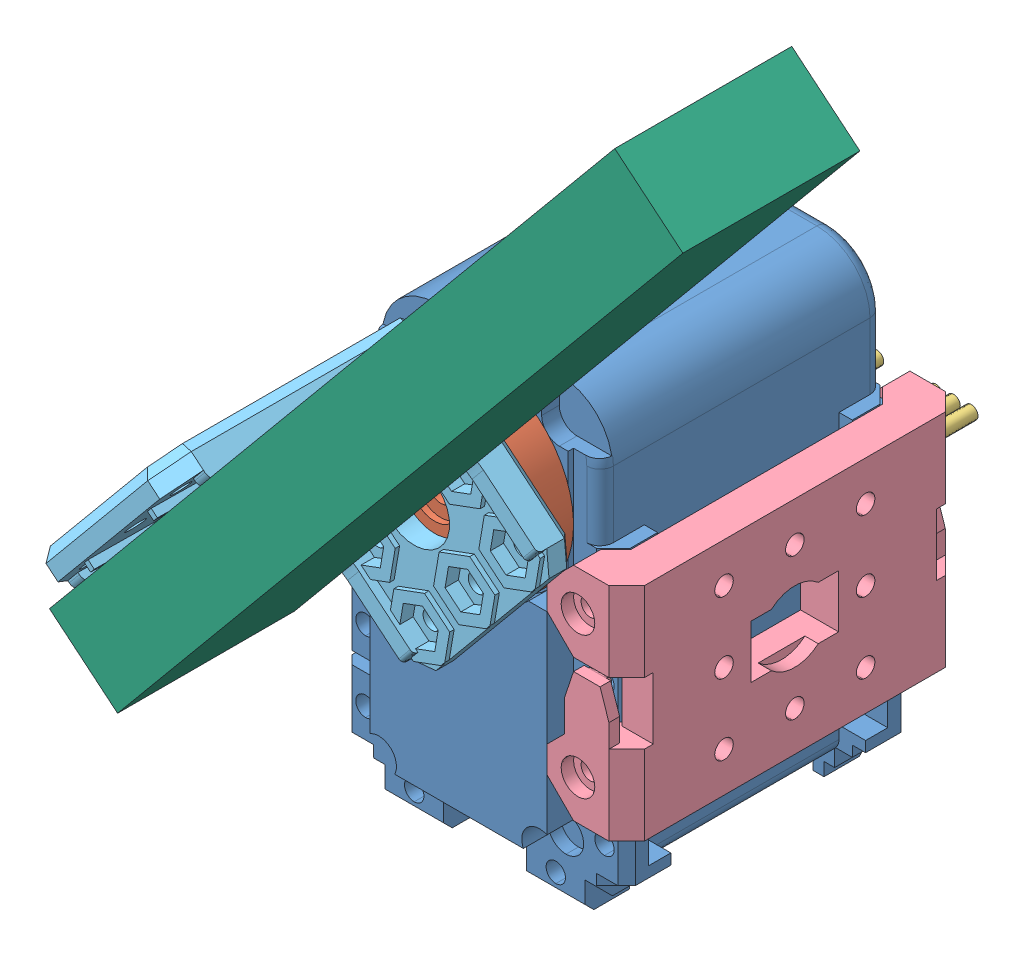
SolidWorks assembly Bras_servo, configuration Défaut. Lengths in mm.
Overall size (74.64 111.64 82.7).
8 component instances, 6 part files, 8 mates.
Components (placement in the parent):
- servomoteur_ax-12-1: servomoteur_ax-12 [Default] at (-3.5987 -0.7426 9.3025) size (32 52.31 53.4)
  - AX-12_modif-1: AX-12_modif [Défaut] at (-2.6768 21.8769 -4.3025) size (32 50.06 38.01)
  - attache_ax-12-1: attache_ax-12 [Default] at (-2.6768 21.8769 12.6975) x (-0.301968 0.953318 0) z (0 0 1) size (22 22 4.7)
  - connecteur_AX-12-1: connecteur_AX-12 [Default] at (6.5732 8.6769 -17.5025) x (-1 0 0) z (0 -1 0) size (8 18.5 4)
  - connecteur_AX-12-2: connecteur_AX-12 [Default] at (-4.0768 8.6769 -17.5025) x (-1 0 0) z (0 -1 0) size (8 18.5 4)
- F3-1: F3 [Défaut] at (12.7285 6.6842 5) x (0 1 0) z (0 0 1) size (25 9 38)
- F9ORG-1: F9ORG [Défaut] at (-15.8942 29.1174 26) x (-0.769498 0.638649 0) z (0 0 -1) size (24 24 30)
- Bras_pour_servo-1: Bras_pour_servo [Défaut] at (-12.785 10.9424 56) x (0.638649 0.769498 0) z (-0.769498 0.638649 0) size (100 20 10)
Mates (geometry in assembly coordinates):
- Coïncidente1: coincident anti-aligned: plane of servomoteur_ax-12-1/AX-12_modif-1 through (-21.8755 -17.2457 21) normal (0 0 1); plane of F3-1 through (9.7285 19.1842 21) normal (0 0 -1)
- Tangent1: tangent: face of servomoteur_ax-12-1/AX-12_modif-1; cylinder of F3-1 through (7.2285 -1.3158 24) axis (0 0 1) radius 1.05
- Tangent2: tangent: face of servomoteur_ax-12-1/AX-12_modif-1; cylinder of F3-1 through (7.2285 14.6842 24) axis (0 0 1) radius 1.05
- Coïncidente2: coincident anti-aligned: plane of servomoteur_ax-12-1/attache_ax-12-1 through (-6.2755 21.1343 26) normal (0 0 1); plane of F9ORG-1 through (-4.3205 3.9172 26) normal (0 0 -1)
- Coaxiale1: concentric aligned: cylinder of servomoteur_ax-12-1/attache_ax-12-1 through (-6.2755 21.1343 26.7) axis (0 0 -1) radius 4; cylinder of F9ORG-1 through (-6.2755 21.1343 26) axis (0 0 -1) radius 4
- Coïncidente9: coincident anti-aligned: plane of F9ORG-1 through (-5.1524 35.7968 30) normal (0.769498 -0.638649 0); plane of Bras_pour_servo-1 through (-20.48 17.3288 36) normal (-0.769498 0.638649 0)
- Coïncidente10: coincident aligned: plane of F9ORG-1 through (-23.558 19.8834 56) normal (0 0 1); plane of Bras_pour_servo-1 through (-20.48 17.3288 56) normal (0 0 1)
- Coïncidente11: coincident aligned: plane of F9ORG-1 through (-23.558 19.8834 26) normal (-0.638649 -0.769498 0); plane of Bras_pour_servo-1 through (-20.48 17.3288 56) normal (-0.638649 -0.769498 0)
